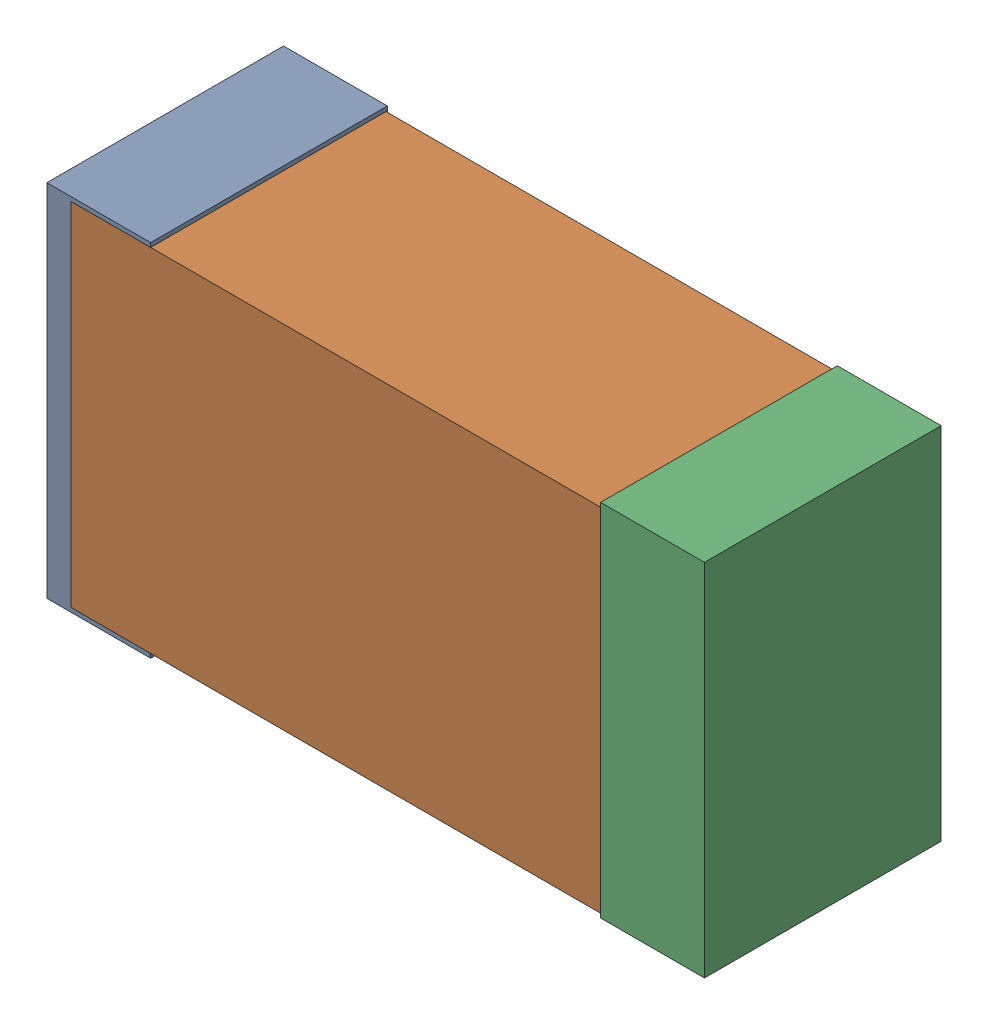
SolidWorks assembly R13, configuration Default. Lengths in mm.
Overall size (2.38 1.3 0.85).
6 component instances, 2 part files, 0 mates.
Components (placement in the parent):
- 384311232-1: 384311232 [Default] at (5.35 67.31 -1.9574) size (0.38 1.3 0.85)
  - Extruded_8-1: Extruded_8 [Default] at origin size (0.38 1.3 0.85)
- 384311360-1: 384311360 [Default] at (6.35 67.31 -1.9524) size (2.2 1.27 0.85)
  - Extruded_9-1: Extruded_9 [Default] at origin size (2.2 1.27 0.85)
- 384311232-2: 384311232 [Default] at (7.35 67.31 -1.9574) size (0.38 1.3 0.85)
  - Extruded_8-1: Extruded_8 [Default] at origin size (0.38 1.3 0.85)
